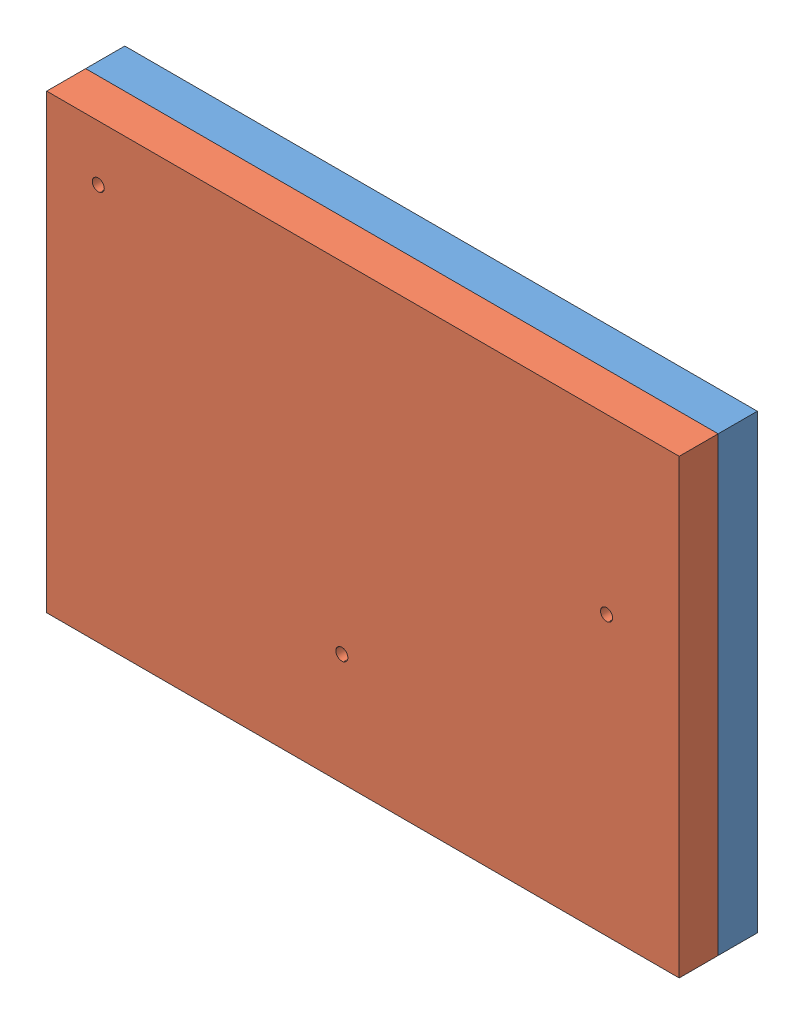
SolidWorks assembly Assemblage1, configuration Défaut. Lengths in mm.
Overall size (210 150 25.94).
2 component instances, 2 part files, 3 mates.
Components (placement in the parent):
- mouleinfinjection2-1: mouleinfinjection2 [Défaut] at (-34.0523 -7.675 210) size (210 150 13)
- moulesupinjection2-1: moulesupinjection2 [Défaut] at (-34.0523 -7.675 222.935) size (210 150 16.93)
Mates (geometry in assembly coordinates):
- Coïncidente1: coincident: plane of mouleinfinjection2-1 through (-34.0523 -7.675 223) normal (0 0 1); plane of moulesupinjection2-1 through (-34.0523 -7.675 223) normal (0 0 -1)
- Coïncidente2: coincident: plane of mouleinfinjection2-1 through (-139.0523 -82.675 223) normal (-1 0 0); plane of moulesupinjection2-1 through (-139.0523 -82.675 235.935) normal (-1 0 0)
- Coïncidente3: coincident aligned: plane of mouleinfinjection2-1 through (-139.0523 67.325 223) normal (0 1 0); plane of moulesupinjection2-1 through (-139.0523 67.325 235.935) normal (0 1 0)
